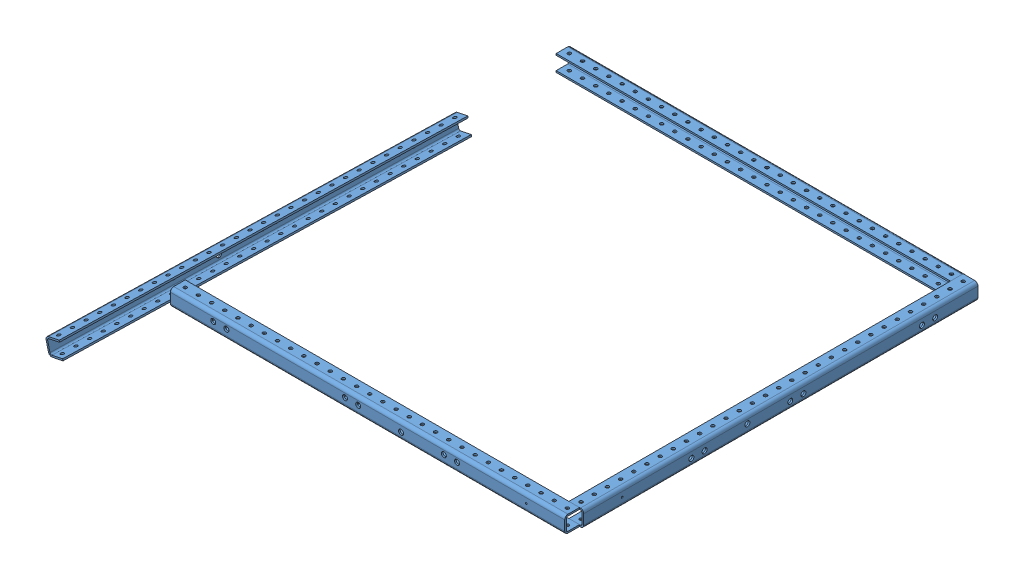
SolidWorks assembly Assem1, configuration Default. Lengths in mm.
Overall size (960.39 181.18 842.6).
4 component instances, 1 part files, 4 mates.
Components (placement in the parent):
- User Library-C channel-1: User Library-C channel [Default] at (-217.5924 342.3251 697.9167) size (760 31.75 28.57)
- User Library-C channel-2: User Library-C channel [Default] at (531.3235 359.671 -71.4633) x (0 0 1) z (1 0 0) size (760 31.75 28.57)
- User Library-C channel-3: User Library-C channel [Default] at (-238.0565 359.671 -88.33) x (1 0 0) z (0 0 -1) size (760 31.75 28.57)
- User Library-C channel-4: User Library-C channel [Default] at (-389.2668 202.1292 6.6279) x (-0.03736 -0.01169 0.999233) z (-0.971538 -0.233641 -0.039058) size (760 31.75 28.57)
Mates (geometry in assembly coordinates):
- Coincident18: coincident anti-aligned: line of User Library-C channel-1 through (526.3876 366.873 672.5167) axis (-1 0 0); line of User Library-C channel-2 through (505.9235 366.873 672.5167) axis (1 0 0)
- Coincident19: coincident aligned: line of User Library-C channel-1 through (-233.6124 335.123 672.5167) axis (1 0 0); line of User Library-C channel-2 through (505.9235 335.123 672.5167) axis (1 0 0)
- Coincident20: coincident aligned: line of User Library-C channel-2 through (505.9235 335.123 672.5167) axis (0 0 -1); line of User Library-C channel-3 through (505.9235 335.123 -62.93) axis (0 0 -1)
- Coincident21: coincident anti-aligned: line of User Library-C channel-2 through (505.9235 366.873 -87.4833) axis (0 0 1); line of User Library-C channel-3 through (505.9235 366.873 -62.93) axis (0 0 -1)
